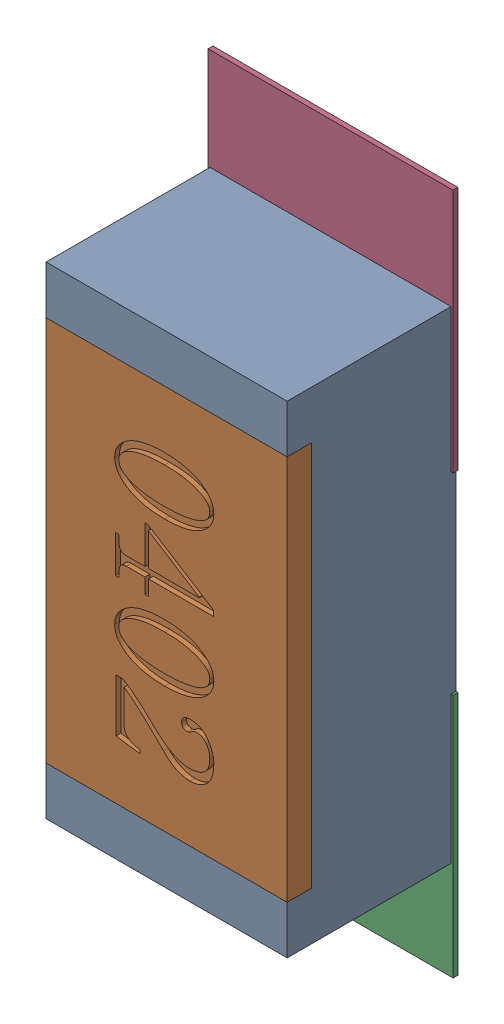
SolidWorks assembly R138, configuration Défaut. Lengths in mm.
Overall size (0.51 1.42 0.35).
5 component instances, 2 part files, 0 mates.
Components (placement in the parent):
- R0402-1: R0402 [Défaut] at (6.9849 -16.9982 0) x (0 -1 0) z (0 0 1) size (1 0.5 0.35)
- 6504207776-1: 6504207776 [Défaut] at (6.985 -17.4482 0) size (0.51 0.51 0.01)
  - Extruded-1: Extruded [Défaut] at origin size (0.51 0.51 0.01)
- 6504207776-2: 6504207776 [Défaut] at (6.985 -16.5411 0) size (0.51 0.51 0.01)
  - Extruded-1: Extruded [Défaut] at origin size (0.51 0.51 0.01)
